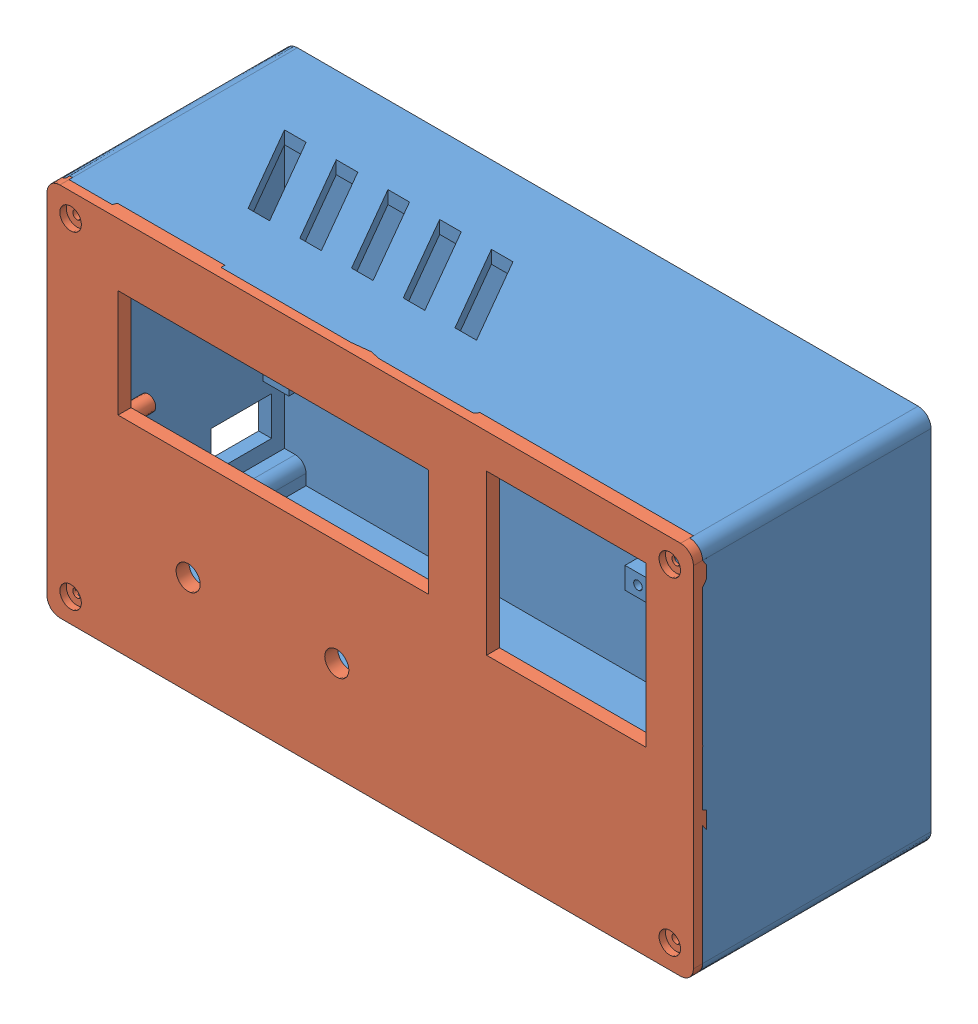
SolidWorks assembly Meter_box, configuration Default. Lengths in mm.
Overall size (150 87 55.12).
2 component instances, 2 part files, 2 mates.
Components (placement in the parent):
- Body-1: Body [Default] at (-48.5048 -93.3357 132.4757) size (150 87 53)
- Cover-1: Cover [Default] at (-48.5048 -93.3357 184.5952) x (1 0 0) z (0 -1 0) size (150 8 87)
Mates (geometry in assembly coordinates):
- Coincident2: coincident aligned: plane of Body-1 through (101.4952 -93.3357 185.4757) normal (1 0 0); plane of Cover-1 through (101.4952 -93.3357 187.5952) normal (1 0 0)
- Coincident3: coincident aligned: plane of Body-1 through (-48.5048 -93.3357 185.4757) normal (0 -1 0); plane of Cover-1 through (-48.5048 -93.3357 187.5952) normal (0 -1 0)
